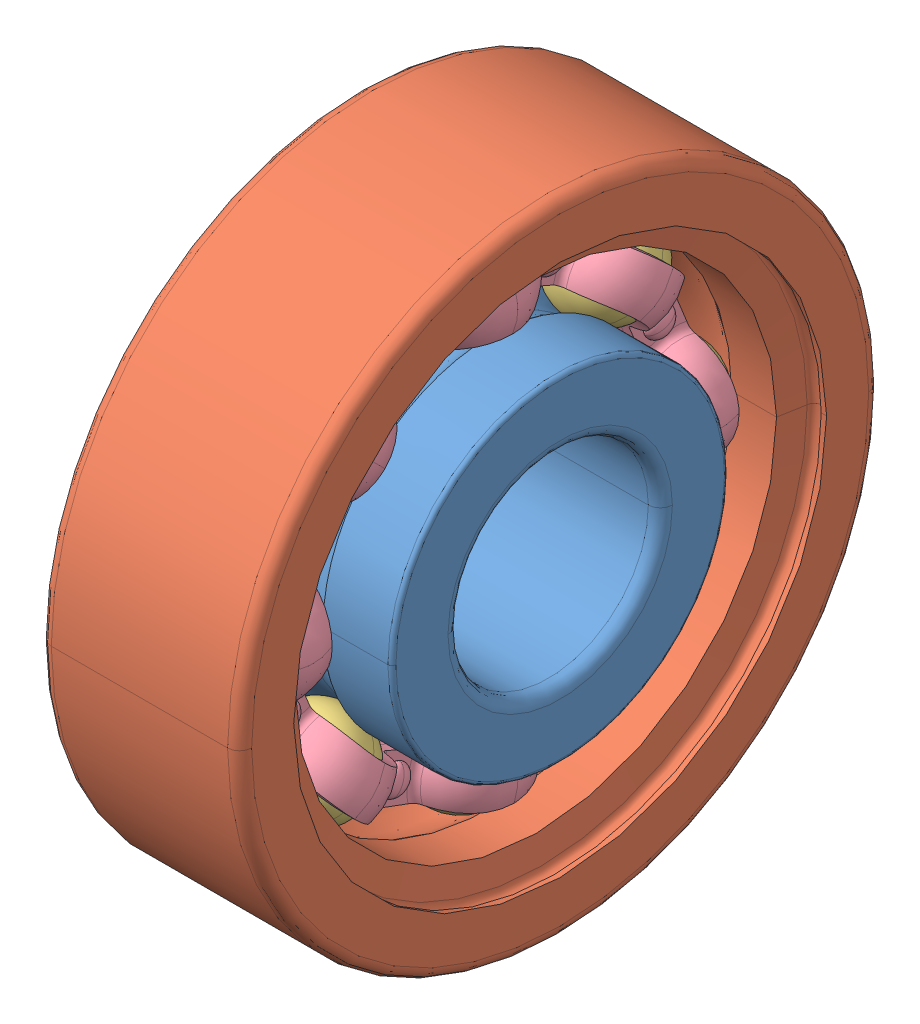
SolidWorks assembly SKF 625, configuration Default. Lengths in mm.
Overall size (5 16 16).
12 component instances, 4 part files, 0 mates.
Components (placement in the parent):
- SKF 625.STEP-1: SKF 625.STEP [Default] at origin size (5 16 16)
  - SKF 625 Inner Race^SKF 625.STEP-1: SKF 625 Inner Race^SKF 625.STEP [Default] at origin size (5 8.4 8.4)
  - SKF 625 Outer Race^SKF 625.STEP-1: SKF 625 Outer Race^SKF 625.STEP [Default] at origin size (5 16 16)
  - SKF 625 Ball^SKF 625.STEP-1: SKF 625 Ball^SKF 625.STEP [Default] at origin size (2.38 2.38 2.38)
  - SKF 625 Ball^SKF 625.STEP-2: SKF 625 Ball^SKF 625.STEP [Default] x (1 0 0) z (0 0.707107 0.707107) size (2.38 2.38 2.38)
  - SKF 625 Ball^SKF 625.STEP-3: SKF 625 Ball^SKF 625.STEP [Default] x (1 0 0) z (0 1 0) size (2.38 2.38 2.38)
  - SKF 625 Ball^SKF 625.STEP-4: SKF 625 Ball^SKF 625.STEP [Default] x (1 0 0) z (0 0.707107 -0.707107) size (2.38 2.38 2.38)
  - SKF 625 Ball^SKF 625.STEP-5: SKF 625 Ball^SKF 625.STEP [Default] x (1 0 0) z (0 0 -1) size (2.38 2.38 2.38)
  - SKF 625 Ball^SKF 625.STEP-6: SKF 625 Ball^SKF 625.STEP [Default] x (1 0 0) z (0 -0.707107 -0.707107) size (2.38 2.38 2.38)
  - SKF 625 Ball^SKF 625.STEP-7: SKF 625 Ball^SKF 625.STEP [Default] x (1 0 0) z (0 -1 0) size (2.38 2.38 2.38)
  - SKF 625 Ball^SKF 625.STEP-8: SKF 625 Ball^SKF 625.STEP [Default] x (1 0 0) z (0 -0.707107 0.707107) size (2.38 2.38 2.38)
  - SKF 625 Cage^SKF 625.STEP-1: SKF 625 Cage^SKF 625.STEP [Default] at (2.5 0 0) x (0 0 -1) z (1 0 0) size (12.17 12.17 2.88)
